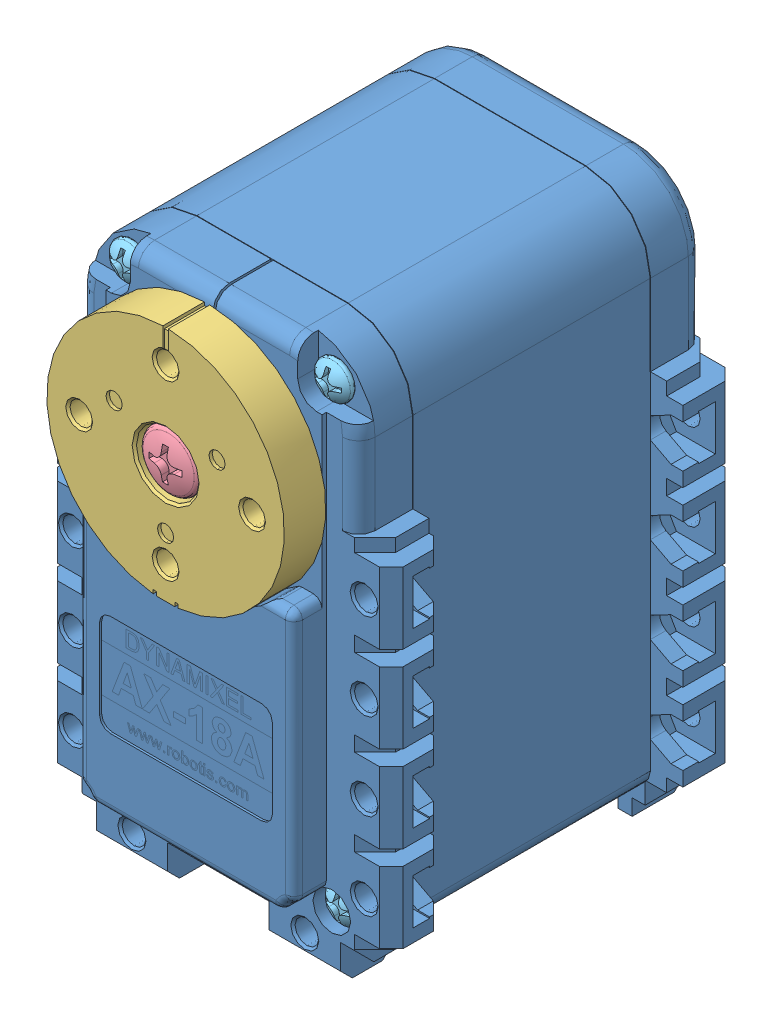
SolidWorks assembly AX-18A, configuration Default. Lengths in mm.
Overall size (32 50.04 40.26).
12 component instances, 7 part files, 19 mates.
Components (placement in the parent):
- Body^AX-18A-1: Body^AX-18A [Défaut] at origin size (32 50.04 38.37) (virtual)
- Horn Assembly^AX-18A-1: Horn Assembly^AX-18A [Default] at (0 0 20.88) x (-1 0 0) z (0 0 1) size (22 22 9.6) (virtual)
  - Wheel Gear^Horn Assembly_AX-18A-1: Wheel Gear^Horn Assembly_AX-18A [Défaut] at (0 0 -22.94) size (6.5 6.5 5.51) (virtual)
  - Horn^Horn Assembly_AX-18A-1: Horn^Horn Assembly_AX-18A [Défaut] at (0 0 -1.84) x (0 -1 0) z (0 0 1) size (22 22 6.7) (virtual)
  - BHS M2x8^Horn Assembly_AX-18A-1: BHS M2x8^Horn Assembly_AX-18A [Défaut] at (0 0 -1.39) x (1 0 0) z (0 -1 0) size (5.5 9.6 5.5) (virtual)
- Cover Screws^AX-18A-2: Cover Screws^AX-18A [Défaut] at (-9.5 8.5 14.5) x (0 1 0) z (1 0 0) size (3.5 30.7 3.5) (virtual)
- 3 Pins Connector^AX-18A-1: 3 Pins Connector^AX-18A [Défaut] at (5.05 -15.19 -9.75) x (1 0 0) z (0 1 0) size (9.9 9.43 4.9) (virtual)
- 3 Pins Connector^AX-18A-2: 3 Pins Connector^AX-18A [Défaut] at (-4.95 -15.19 -9.75) x (1 0 0) z (0 1 0) size (9.9 9.43 4.9) (virtual)
- Insert M3^AX-18A-1: Insert M3^AX-18A [Défaut] at (0 0 -18.4) x (-1 0 0) z (0 1 0) size (4.98 7 4.98) (virtual)
- Cover Screws^AX-18A-5: Cover Screws^AX-18A [Défaut] at (9.5 8.5 14.5) x (0 1 0) z (1 0 0) size (3.5 30.7 3.5) (virtual)
- Cover Screws^AX-18A-6: Cover Screws^AX-18A [Défaut] at (-10.5 -33 14.5) x (0 1 0) z (1 0 0) size (3.5 30.7 3.5) (virtual)
- Cover Screws^AX-18A-7: Cover Screws^AX-18A [Défaut] at (10.5 -33 14.5) x (0 1 0) z (1 0 0) size (3.5 30.7 3.5) (virtual)
Mates (geometry in assembly coordinates):
- Verrouiller1: lock: unknown of Body^AX-18A-1; unknown of 3 Pins Connector^AX-18A-1
- Verrouiller2: lock: unknown of Body^AX-18A-1; unknown of 3 Pins Connector^AX-18A-2
- Verrouiller3: lock: unknown of Body^AX-18A-1; unknown of Insert M3^AX-18A-1
- Coaxiale6: concentric anti-aligned: cylinder of Body^AX-18A-1 through (-9.5 8.5 19) axis (0 0 1) radius 1.035; cylinder of Cover Screws^AX-18A-2 through (-9.5 8.5 15.675) axis (0 0 -1) radius 0.8
- Coïncidente10: coincident anti-aligned: plane of Body^AX-18A-1 through (0 0 14.5) normal (0 0 1); plane of Cover Screws^AX-18A-2 through (-9.5 8.5 14.5) normal (0 0 -1)
- Coaxiale7: concentric anti-aligned: cylinder of Body^AX-18A-1 through (9.5 8.5 19) axis (0 0 1) radius 1.035; cylinder of Cover Screws^AX-18A-5 through (9.5 8.5 15.675) axis (0 0 -1) radius 0.8
- Coïncidente11: coincident anti-aligned: plane of Body^AX-18A-1 through (0 0 14.5) normal (0 0 1); plane of Cover Screws^AX-18A-5 through (9.5 8.5 14.5) normal (0 0 -1)
- Coaxiale8: concentric anti-aligned: cylinder of Body^AX-18A-1 through (-10.5 -33 19) axis (0 0 1) radius 1.035; cylinder of Cover Screws^AX-18A-6 through (-10.5 -33 15.675) axis (0 0 -1) radius 0.8
- Coïncidente12: coincident anti-aligned: plane of Body^AX-18A-1 through (0 0 14.5) normal (0 0 1); plane of Cover Screws^AX-18A-6 through (-10.5 -33 14.5) normal (0 0 -1)
- Coaxiale9: concentric anti-aligned: cylinder of Body^AX-18A-1 through (10.5 -33 19) axis (0 0 1) radius 1.035; cylinder of Cover Screws^AX-18A-7 through (10.5 -33 15.675) axis (0 0 -1) radius 0.8
- Coïncidente13: coincident anti-aligned: plane of Body^AX-18A-1 through (0 0 14.5) normal (0 0 1); plane of Cover Screws^AX-18A-7 through (10.5 -33 14.5) normal (0 0 -1)
- Parallèle5: parallel aligned: plane of Cover Screws^AX-18A-5 through (10.7327 8.2929 15.1) normal (0 1 0); plane of Cover Screws^AX-18A-7 through (11.7327 -33.2071 15.1) normal (0 1 0)
- Parallèle6: parallel aligned: plane of Cover Screws^AX-18A-2 through (-8.2673 8.2929 15.1) normal (0 1 0); plane of Cover Screws^AX-18A-5 through (10.7327 8.2929 15.1) normal (0 1 0)
- Parallèle7: parallel aligned: plane of Cover Screws^AX-18A-6 through (-9.2673 -33.2071 15.1) normal (0 1 0); plane of Cover Screws^AX-18A-7 through (11.7327 -33.2071 15.1) normal (0 1 0)
- Parallèle8: parallel aligned: plane of Body^AX-18A-1 through (0.1 6.75 16.4) normal (-1 0 0); plane of Cover Screws^AX-18A-2 through (-9.2929 9.7327 15.1) normal (-1 0 0)
- Coaxiale10: concentric anti-aligned: cylinder of Body^AX-18A-1 through (0 0 16.4) axis (0 0 1) radius 4.6; cone of Horn Assembly^AX-18A-1/Horn^Horn Assembly_AX-18A-1 through (0 0 17.04) axis (0 0 -1)
- Distance3: distance = 1.88 mm aligned: plane of Horn Assembly^AX-18A-1/Horn^Horn Assembly_AX-18A-1 through (0 0 20.88) normal (0 0 1); plane of Body^AX-18A-1 through (0 0 19) normal (0 0 1)
- Parallèle9: parallel aligned: plane of Body^AX-18A-1 through (-0.1 6.75 16.1) normal (1 0 0); plane of Horn Assembly^AX-18A-1/Horn^Horn Assembly_AX-18A-1 through (-0.2472 10.9972 21.04) normal (1 0 0)
- AngleLimite1: limit planar angle = 0.100093 rad aligned: plane of Horn Assembly^AX-18A-1/Horn^Horn Assembly_AX-18A-1 through (0.8529 10.9669 21.04) normal (0.994995 -0.099926 0); plane of Body^AX-18A-1 through (-0.1 6.75 16.1) normal (1 0 0)
